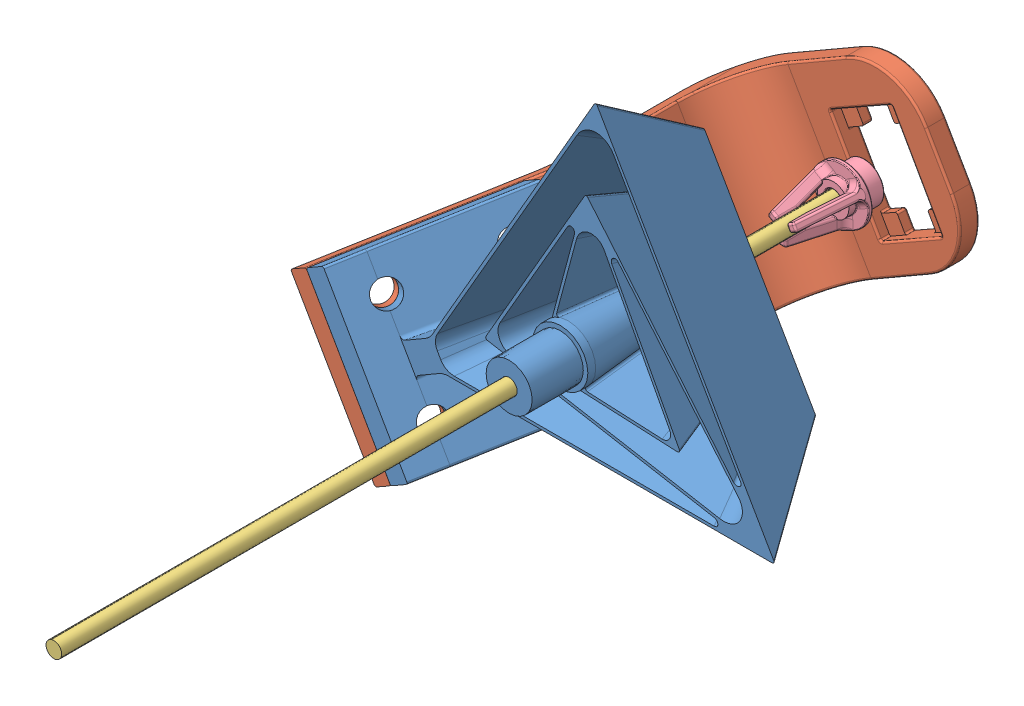
SolidWorks assembly Assembly, configuration Default. Lengths in mm.
Overall size (128.68 112.47 234.98).
4 component instances, 4 part files, 10 mates.
Components (placement in the parent):
- circular fixture joint-1: circular fixture joint [Default] at origin size (111.32 102.51 101.36)
- sensor base-1: sensor base [Default] at (-1.5133 -1.2191 -15.5668) x (-0.418519 -0.220271 0.881091) z (-0.492342 0.870249 -0.016302) size (117.83 42.41 44.06)
- whisker 4x200mm-1: whisker 4x200mm [Default] at (38 20 30.6813) x (0.44178 0.897123 0) z (0 0 1) size (4 4 200)
- Chuck Base-1: Chuck Base [Default] at (38 20 -69.3187) x (0 -1 0) z (-1 0 0) size (14 21 14)
Mates (geometry in assembly coordinates):
- Coincident1: coincident aligned: plane of circular fixture joint-1 through (0 0 0) normal (0 0 1)
- Coincident2: coincident aligned: plane of circular fixture joint-1 through (0 0 0) normal (0 1 0)
- Coincident3: coincident aligned: plane of circular fixture joint-1 through (0 0 0) normal (1 0 0)
- Coincident4: coincident anti-aligned: plane of circular fixture joint-1 through (1.3218 24.6195 -40) normal (-0.763178 -0.440621 -0.472665); plane of sensor base-1 through (0.0131 -0.3378 -14.6215) normal (0.763178 0.440621 0.472665)
- Concentric2: concentric anti-aligned: cylinder of circular fixture joint-1 through (90.0487 37.499 53.4173) axis (-0.763178 -0.440621 -0.472665) radius 3.15; cylinder of sensor base-1 through (-9.511 -19.9818 -8.2437) axis (0.763178 0.440621 0.472665) radius 3.15
- Parallel4: parallel anti-aligned: cylinder of circular fixture joint-1 through (100.5134 43.0068 31.3862) axis (-0.763178 -0.440621 -0.472665) radius 3.15; cylinder of sensor base-1 through (0.952 -14.475 -30.271) axis (0.763178 0.440621 0.472665) radius 3.15
- Parallel7: parallel aligned: line of circular fixture joint-1 through (-20.9462 12.3404 7.4012) axis (0.5 -0.866025 0); line of sensor base-1 through (-20.9517 12.345 7.4058) axis (0.5 -0.866025 0)
- Concentric3: concentric anti-aligned: cylinder of circular fixture joint-1 through (38 20 -40.0003) axis (0 0 1) radius 2.05; cylinder of whisker 4x200mm-1 through (38 20 130.6813) axis (0 0 -1) radius 2
- Concentric4: concentric aligned: cylinder of whisker 4x200mm-1 through (38 20 130.6813) axis (0 0 -1) radius 2; cylinder of Chuck Base-1 through (38 20 -67.3187) axis (0 0 -1) radius 2.25
- Coincident5: coincident anti-aligned: plane of whisker 4x200mm-1 through (38 20 -69.3187) normal (0 0 -1); plane of Chuck Base-1 through (38 13 -69.3187) normal (0 0 1)
